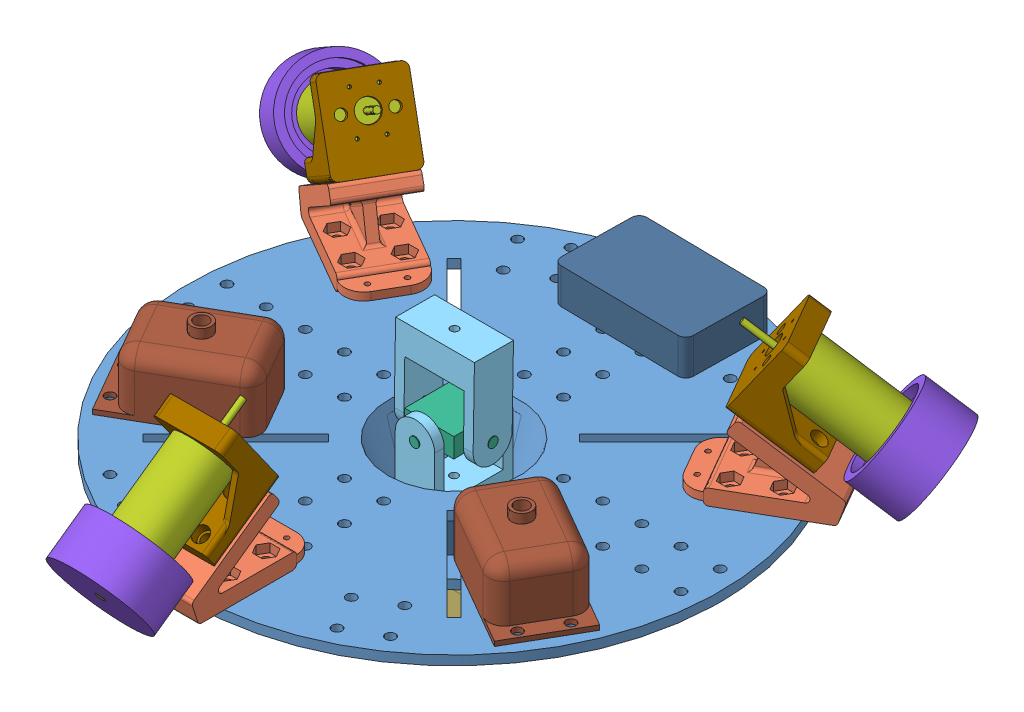
SolidWorks assembly LAT2_0, configuration Default. Lengths in mm.
Overall size (481.2 212.31 432.17).
26 component instances, 13 part files, 16 mates.
Components (placement in the parent):
- BodyPlate-1: BodyPlate [Default] at (178.0049 202.6819 325.7641) size (345.3 46.25 345.3)
- angle35withMarker-1: angle35withMarker [Default] at (26.4001 202.6819 212.5718) x (0.866025 0 0.5) z (-0.5 0 0.866025) size (80.26 49.82 44.45)
- controlMount-1: controlMount [Default] at (210.4083 156.4319 288.69) x (-0.997622 0 0.06892) z (0.06892 0 0.997622) size (66.04 40.64 66.04)
- Part1^LAT2_0-1: Part1^LAT2_0 [Default] at origin (virtual)
- angle35withMarker-2: angle35withMarker [Default] at (351.8348 202.6819 251.0666) x (-0.866025 0 0.5) z (-0.5 0 -0.866025) size (80.26 49.82 44.45)
- angle35withMarker-3: angle35withMarker [Default] at (155.7799 202.6819 513.6539) x (0 0 -1) z (1 0 0) size (80.26 49.82 44.45)
- battery-1: battery [Default] at (229.3862 125.9519 301.3823) x (0.06892 0 0.997622) z (-0.997622 0 0.06892) size (34 22 105)
- Part2^LAT2_0-1: Part2^LAT2_0 [Default] at origin (virtual)
- hang1-1: hang1 [Default] at (182.1719 199.1518 300.2946) x (0.999989 0 -0.004631) z (0.004631 0 0.999989) size (25.45 63.45 50.9)
- hang2-1: hang2 [Default] at (222.8402 223.756 309.9063) x (0.999971 -0.006068 -0.004631) z (0.004631 0 0.999989) size (51.4 12.7 51.4)
- hang1-2: hang1 [Default] at (152.4112 227.3628 330.2671) x (0.004696 0.010727 0.999931) z (0.999971 -0.006068 -0.004631) size (25.45 63.45 50.9)
- RWMotor-1: RWMotor [Default] at (315.3203 185.1163 146.0312) x (-0.707145 0.577288 0.40827) z (0.603382 0.793707 -0.0772) size (113.8 86 86)
  - motor_withshaft-1: motor_withshaft [Default] at (114.1916 63.2299 66.0433) size (113.8 34.9 34.9)
  - reactionWheel_noshaft-1: reactionWheel_noshaft [Default] at (21.0703 73.5429 66.0433) x (0 -0.760425 0.649425) z (0 0.649425 0.760425) size (61 30.5 61)
  - reactionWheelMount-1: reactionWheelMount [Default] at (52.024 80.7007 36.4157) x (0 -0.972036 -0.234834) z (0 -0.234834 0.972036) size (44.45 50.8 50.8)
- RWMotor-2: RWMotor [Default] at (265.0005 185.1163 534.5492) x (0 0.577288 -0.816541) z (-0.234834 0.793707 0.561144) size (113.8 86 86)
  - motor_withshaft-1: motor_withshaft [Default] at (114.1916 63.2299 66.0433) size (113.8 34.9 34.9)
  - reactionWheel_noshaft-1: reactionWheel_noshaft [Default] at (21.0703 73.5429 66.0433) x (0 -0.760425 0.649425) z (0 0.649425 0.760425) size (61 30.5 61)
  - reactionWheelMount-1: reactionWheelMount [Default] at (52.024 80.7007 36.4157) x (0 -0.972036 -0.234834) z (0 -0.234834 0.972036) size (44.45 50.8 50.8)
- RWMotor-3: RWMotor [Default] at (-46.3061 185.1163 296.7119) x (0.707145 0.577288 0.40827) z (-0.368548 0.793707 -0.483944) size (113.8 86 86)
  - motor_withshaft-1: motor_withshaft [Default] at (114.1916 63.2299 66.0433) size (113.8 34.9 34.9)
  - reactionWheel_noshaft-1: reactionWheel_noshaft [Default] at (21.0703 73.5429 66.0433) x (0 -0.760425 0.649425) z (0 0.649425 0.760425) size (61 30.5 61)
  - reactionWheelMount-1: reactionWheelMount [Default] at (52.024 80.7007 36.4157) x (0 -0.972036 -0.234834) z (0 -0.234834 0.972036) size (44.45 50.8 50.8)
- boards-1: boards [Default] at (195.8116 202.6819 178.2523) x (0.015069 0 -0.999886) z (0.999886 0 0.015069) size (55 23 87)
- FuelTank-1: FuelTank [Default] at (86.6253 223.1819 407.3897) x (-0.5 0 -0.866025) z (-0.866025 0 0.5) size (50 44 80)
- FuelTank-2: FuelTank [Default] at (294.3845 223.1819 364.0884) x (-0.5 0 0.866025) z (0.866025 0 0.5) size (50 44 80)
Mates (geometry in assembly coordinates):
- Concentric1: concentric aligned: cylinder of BodyPlate-1 through (55.1314 156.4319 269.4877) axis (0 1 0) radius 3.2; circle of angle35withMarker-1
- Concentric2: concentric aligned: circle of BodyPlate-1; circle of angle35withMarker-1
- Coincident1: coincident anti-aligned: plane of BodyPlate-1 through (220.6547 202.6819 325.7641) normal (0 1 0); plane of angle35withMarker-1 through (4.1751 202.6819 251.0666) normal (0 -1 0)
- Coincident3: coincident anti-aligned: plane of BodyPlate-1 through (233.5049 156.4319 325.7641) normal (0 -1 0); plane of controlMount-1 through (214.9597 156.4319 354.573) normal (0 1 0)
- Coincident4: coincident anti-aligned: plane of controlMount-1 through (145.4881 125.9519 307.1783) normal (0 1 0); plane of battery-1 through (124.7737 125.9519 310.6141) normal (0 -1 0)
- Coincident5: coincident anti-aligned: plane of controlMount-1 through (145.4881 156.4319 307.1783) normal (0.06892 0 0.997622); plane of battery-1 through (124.6359 127.9519 308.6188) normal (-0.06892 0 -0.997622)
- Coincident9: coincident anti-aligned: plane of BodyPlate-1 through (178.0049 162.4319 325.7641) normal (0 1 0); plane of hang1-1 through (165.3979 162.4319 351.2728) normal (0 -1 0)
- Concentric6: concentric anti-aligned: circle of BodyPlate-1; circle of hang1-1
- Coincident10: coincident aligned: circle of hang1-1; circle of hang2-1
- Coincident11: coincident aligned: circle of hang2-1; circle of hang1-2
- Coincident12: coincident anti-aligned: circle of angle35withMarker-2; circle of RWMotor-1/reactionWheelMount-1
- Concentric7: concentric anti-aligned: circle of angle35withMarker-2; circle of RWMotor-1/reactionWheelMount-1
- Coincident14: coincident anti-aligned: plane of BodyPlate-1 through (220.6547 202.6819 325.7641) normal (0 1 0); plane of boards-1 through (216.0668 202.6819 213.5015) normal (0 -1 0)
- Coincident15: coincident anti-aligned: plane of BodyPlate-1 through (220.6547 202.6819 325.7641) normal (0 1 0); plane of FuelTank-1 through (86.6253 202.6819 407.3897) normal (0 -1 0)
- Concentric10: concentric anti-aligned: circle of BodyPlate-1; circle of FuelTank-1
- Concentric11: concentric anti-aligned: circle of BodyPlate-1; circle of FuelTank-1
